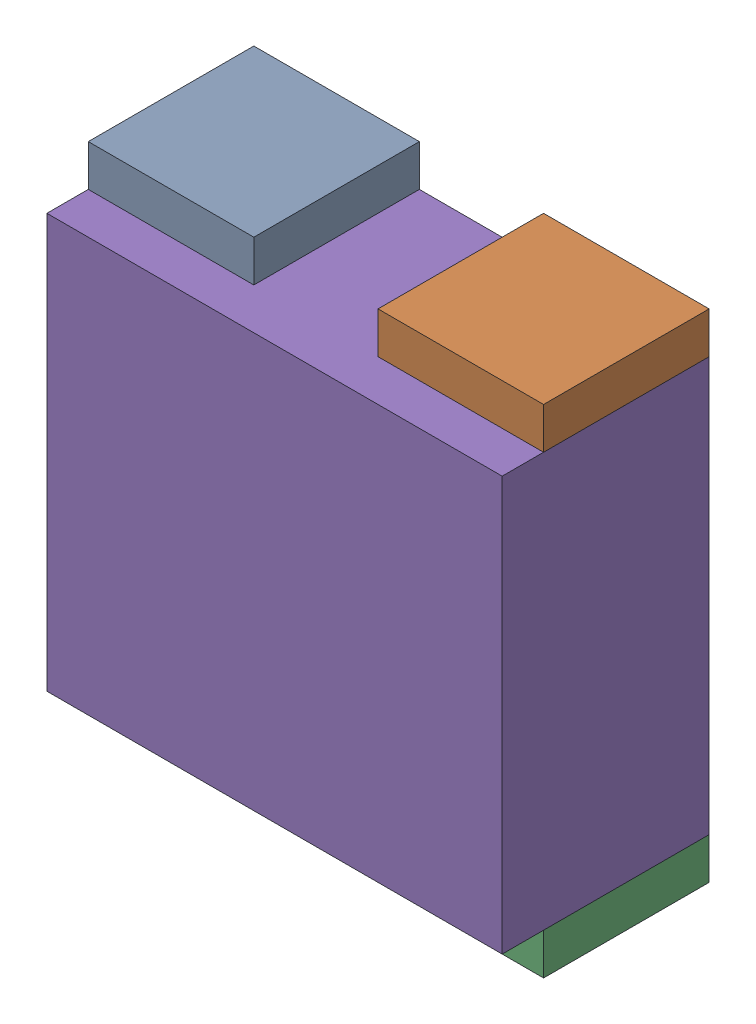
SolidWorks assembly RN22, configuration Default. Lengths in mm.
Overall size (1.1 1.2 0.5).
10 component instances, 2 part files, 0 mates.
Components (placement in the parent):
- 810157616-1: 810157616 [Default] at (129.95 79 0) size (0.4 0.1 0.4)
  - Extruded_12-1: Extruded_12 [Default] at origin size (0.4 0.1 0.4)
- 810157616-2: 810157616 [Default] at (130.65 79 0) size (0.4 0.1 0.4)
  - Extruded_12-1: Extruded_12 [Default] at origin size (0.4 0.1 0.4)
- 810157616-3: 810157616 [Default] at (130.65 77.9 0) size (0.4 0.1 0.4)
  - Extruded_12-1: Extruded_12 [Default] at origin size (0.4 0.1 0.4)
- 810157616-4: 810157616 [Default] at (129.95 77.9 0) size (0.4 0.1 0.4)
  - Extruded_12-1: Extruded_12 [Default] at origin size (0.4 0.1 0.4)
- 810156720-1: 810156720 [Default] at (130.3 78.45 0) size (1.1 1 0.5)
  - Extruded_13-1: Extruded_13 [Default] at origin size (1.1 1 0.5)
